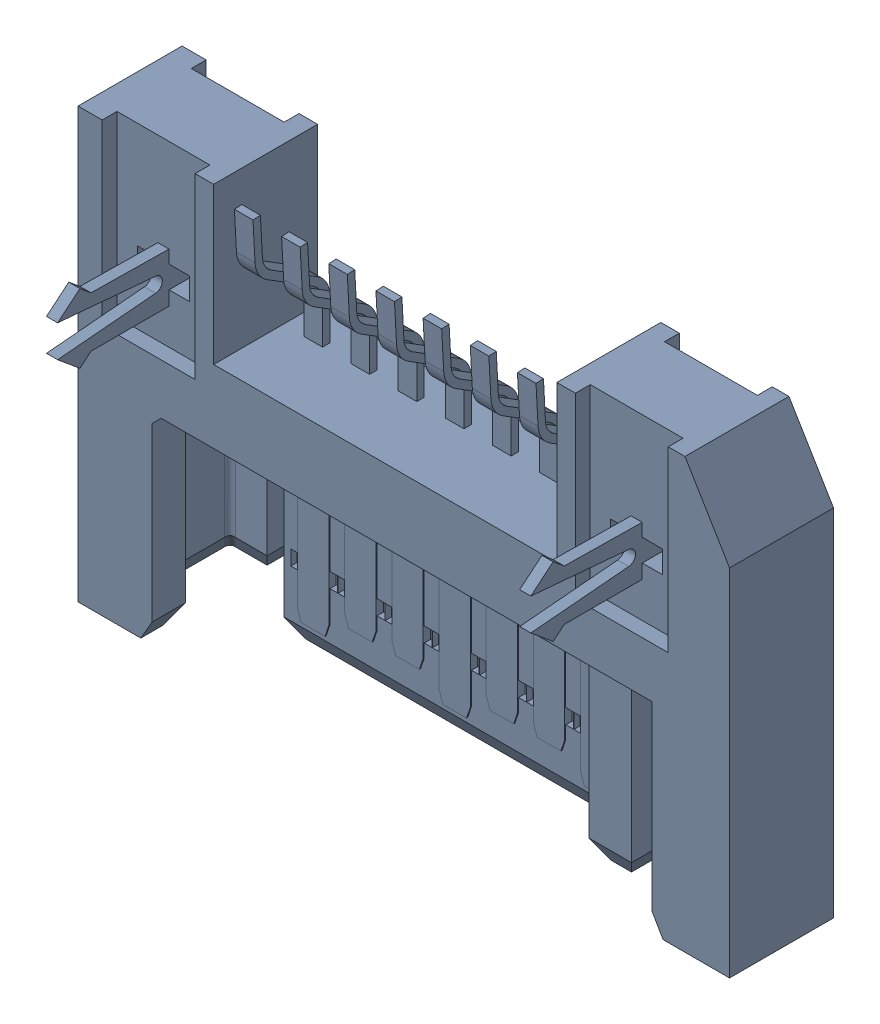
SolidWorks assembly SATA, configuration Default. Lengths in mm.
Overall size (17.54 11.56 6.6).
2 component instances, 1 part files, 0 mates.
Components (placement in the parent):
- sata_1-1: sata_1 [Default] at (47.5741 5.8166 -3.1024) x (1 0 0) z (0 -1 0) size (17.54 6.6 11.56)
  - Open CASCADE STEP translator 6.2 1.2.1.1-1: Open CASCADE STEP translator 6.2 1.2.1.1 [Default] at origin size (17.54 6.6 11.56)
